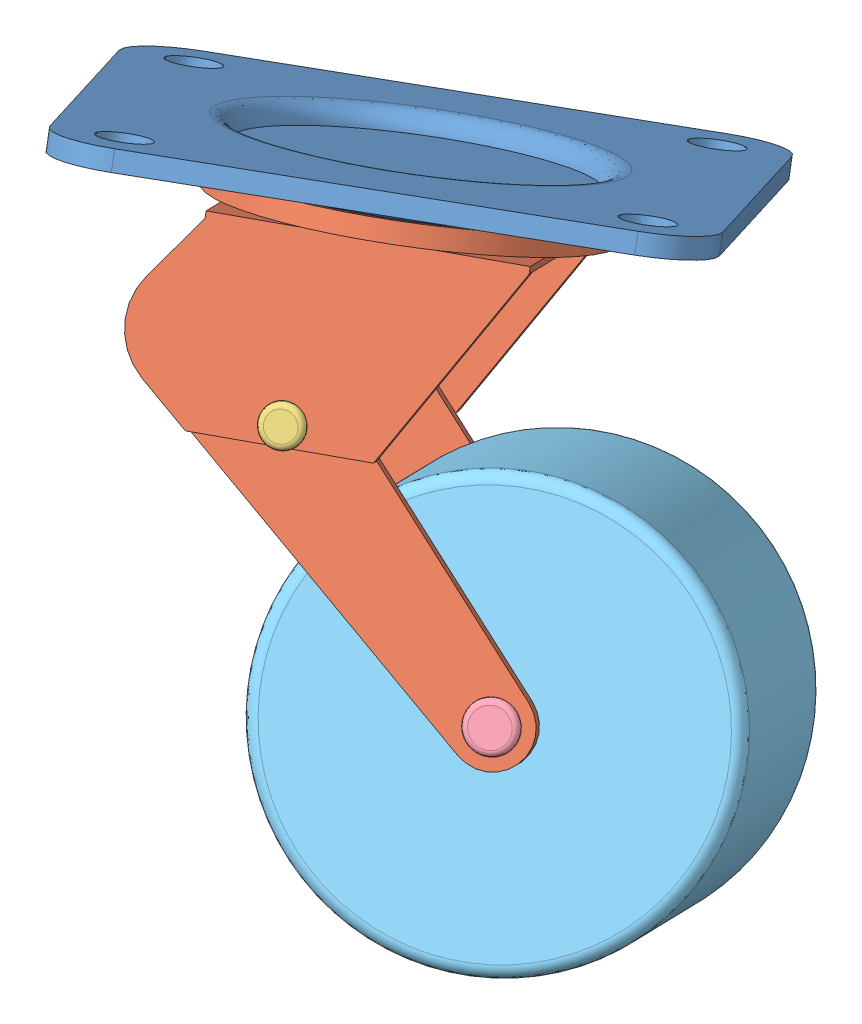
SolidWorks assembly caster wheel assembly, configuration Default. Lengths in mm.
Overall size (148.85 134.47 125.9).
5 component instances, 5 part files, 12 mates.
Components (placement in the parent):
- top base-1: top base [Default] at (19.5857 26.2925 87.0635) x (0.81983 -0.064266 -0.568989) z (0.532669 0.450196 0.71665) size (90 8.4 90)
- base and wheel link-1: base and wheel link [Default] at (20.258 23.4425 88.3541) x (0.861451 -0.026444 -0.507152) z (0.462341 0.453991 0.761664) size (61.73 70.8 56)
- shaft 2-2: shaft 2 [Default] at (19.6721 -2.7716 104.3347) x (-0.462341 -0.453991 -0.761664) z (0.096265 -0.879608 0.465857) size (55 6.67 6.67)
- wheel shaft-2: wheel shaft [Default] at (55.4844 -35.5586 102.1388) x (-0.462341 -0.453991 -0.761664) z (0.88034 -0.13231 -0.455516) size (51 8 8)
- wheel-2: wheel [Default] at (45.0061 -45.1452 84.6728) x (0.462341 0.453991 0.761664) z (-0.761664 -0.236462 0.603285) size (45 67.6 67.6)
Mates (geometry in assembly coordinates):
- Concentric1: concentric aligned: cylinder of top base-1 through (20.6782 21.6613 89.1608) axis (-0.210101 0.890614 -0.403317) radius 25; cylinder of Part1-1 through (20.6782 21.6613 89.1608) axis (-0.210101 0.890614 -0.403317) radius 25
- Coincident1: coincident anti-aligned: plane of top base-1 through (20.6782 21.6613 89.1608) normal (0.210101 -0.890614 0.403317); plane of Part1-1 through (20.6782 21.6613 89.1608) normal (-0.210101 0.890614 -0.403317)
- Concentric2: concentric aligned: cylinder of Part1-1 through (42.4633 -47.6421 80.4837) axis (0.462341 0.453991 0.761664) radius 3.5; cylinder of wheel-1 through (45.0061 -45.1452 84.6728) axis (0.462341 0.453991 0.761664) radius 3.5
- Coincident2: coincident anti-aligned: plane of Part1-1 through (65.8115 -24.7156 118.9477) normal (-0.462341 -0.453991 -0.761664); plane of wheel-1 through (49.7467 -11.3055 120.7062) normal (0.462341 0.453991 0.761664)
- Concentric4: concentric aligned: cylinder of Part1-1 through (6.7265 -15.4833 83.0081) axis (0.462341 0.453991 0.761664) radius 2.5; cylinder of shaft 2-1 through (19.1751 -3.2596 103.5159) axis (0.462341 0.453991 0.761664) radius 2.5
- Concentric5: concentric aligned: cylinder of Part1-1 through (6.7265 -15.4833 83.0081) axis (0.462341 0.453991 0.761664) radius 2.5; cylinder of shaft 2-2 through (32.3865 9.7132 125.2805) axis (0.462341 0.453991 0.761664) radius 2.5
- Coincident4: coincident anti-aligned: plane of Part1-1 through (14.2305 33.2051 120.9862) normal (0.462341 0.453991 0.761664); plane of shaft 2-2 through (29.7205 9.6144 125.6448) normal (-0.462341 -0.453991 -0.761664)
- Concentric6: concentric anti-aligned: cylinder of Part1-1 through (42.4633 -47.6421 80.4837) axis (0.462341 0.453991 0.761664) radius 3.5; cylinder of wheel shaft-1 through (81.1673 -9.6372 144.2449) axis (-0.462341 -0.453991 -0.761664) radius 3.5
- Concentric7: concentric aligned: cylinder of Part1-1 through (42.4633 -47.6421 80.4837) axis (0.462341 0.453991 0.761664) radius 3.5; cylinder of wheel shaft-2 through (67.1985 -23.3536 121.2327) axis (0.462341 0.453991 0.761664) radius 3.5
- Coincident6: coincident anti-aligned: plane of Part1-1 through (66.7362 -23.8076 120.4711) normal (0.462341 0.453991 0.761664); plane of wheel shaft-2 through (67.1073 -26.8915 122.084) normal (-0.462341 -0.453991 -0.761664)
- Concentric8: concentric anti-aligned: cylinder of wheel shaft-2 through (67.1985 -23.3536 121.2327) axis (0.462341 0.453991 0.761664) radius 3.5; cylinder of wheel-2 through (65.8115 -24.7156 118.9477) axis (-0.462341 -0.453991 -0.761664) radius 3.5
- Coincident7: coincident anti-aligned: plane of Part1-1 through (45.0061 -45.1452 84.6728) normal (0.462341 0.453991 0.761664); plane of wheel-2 through (29.6613 -16.1091 76.6804) normal (-0.462341 -0.453991 -0.761664)
